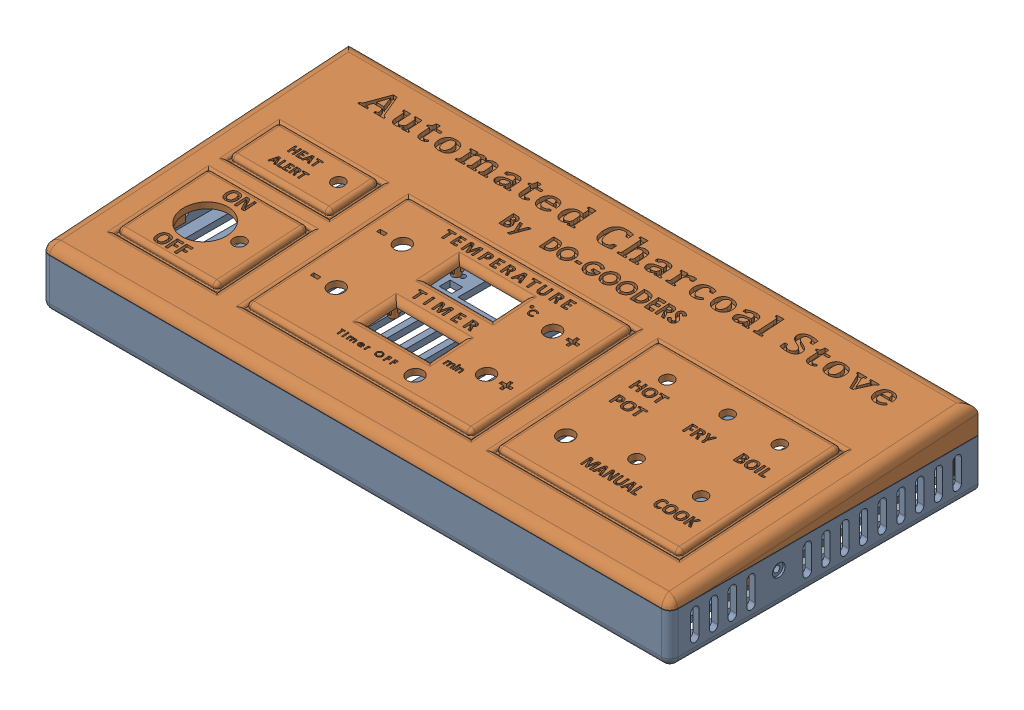
SolidWorks assembly Assem1, configuration Default. Lengths in mm.
Overall size (302 37.84 148).
2 component instances, 2 part files, 2 mates.
Components (placement in the parent):
- Bottom-1: Bottom [Default] at (-165.4643 -15.2604 83.8477) size (302 24 148)
- TOP_Last-1: TOP_Last [Default] at (136.5357 -6.067 83.8477) size (302 28.65 148)
Mates (geometry in assembly coordinates):
- Coincident2: coincident aligned: plane of Bottom-1 through (136.5357 -15.2604 -64.1523) normal (0 0 -1); plane of TOP_Last-1 through (-165.4643 -6.067 -64.1523) normal (0 0 -1)
- Coincident3: coincident aligned: plane of Bottom-1 through (136.5357 -15.2604 83.8477) normal (1 0 0); plane of TOP_Last-1 through (136.5357 -6.067 83.8477) normal (1 0 0)
